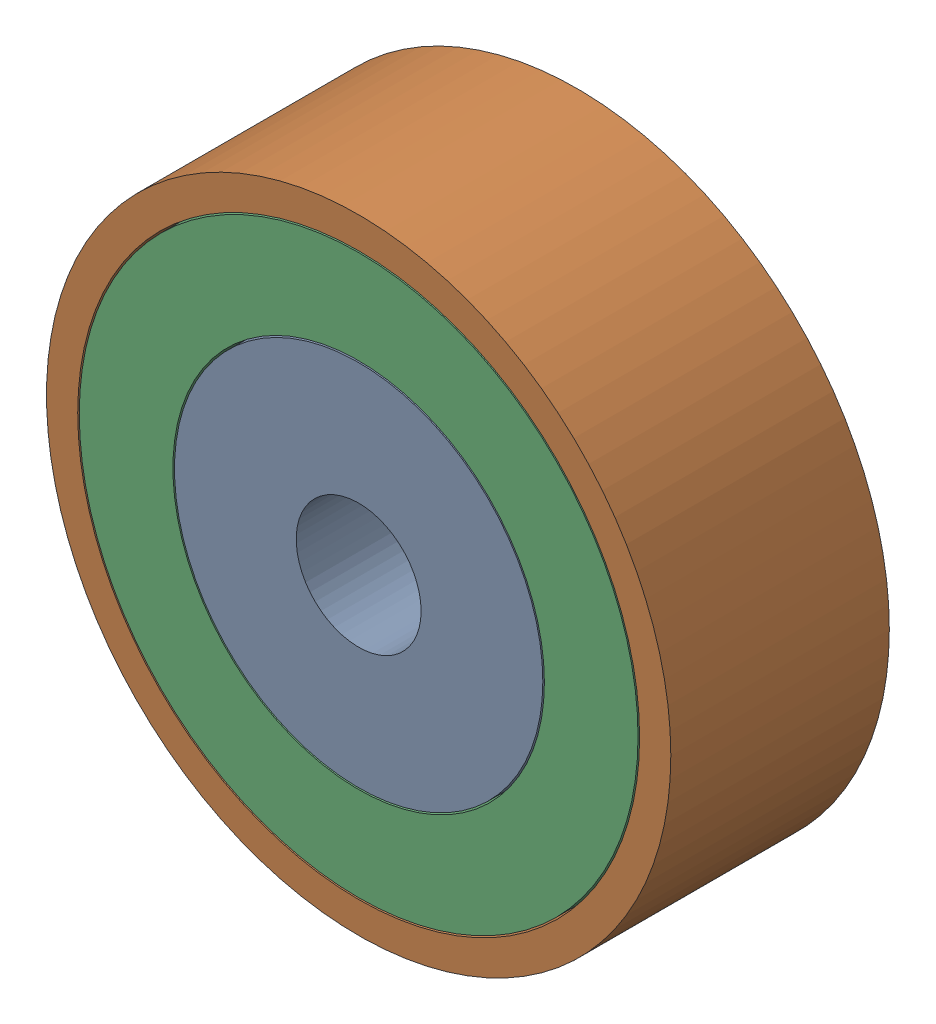
SolidWorks assembly 镜向轴承9, configuration 默认. Lengths in mm.
Overall size (20 20 7).
3 component instances, 3 part files, 4 mates.
Components (placement in the parent):
- 镜向轴承内圈-1: 镜向轴承内圈 [默认] at (-5.0655 0.8032 -6.5) size (11.8 11.8 7)
- 镜向轴承外圈-1: 镜向轴承外圈 [默认] at (-5.0655 0.8032 -6.5) size (20 20 7)
- 镜向轴承中圈-1: 镜向轴承中圈 [默认] at (-5.0655 0.8032 -6.5) size (17.9 17.9 7)
Mates (geometry in assembly coordinates):
- 重合1: coincident: plane of ? through (-5.0655 0.8032 -13.5) normal (0 0 -1); plane of ? through (-5.0655 0.8032 -13.5) normal (0 0 -1)
- 重合2: coincident: plane of ? through (-5.0655 0.8032 -13.5) normal (0 0 -1); plane of ? through (-5.0655 0.8032 -13.5) normal (0 0 -1)
- 同心1: concentric: cylinder of ? through (-5.0655 0.8032 -13.5) axis (0 0 1) radius 9; cylinder of ? through (-5.0655 0.8032 -13.5) axis (0 0 1) radius 8.95
- 同心2: concentric: cylinder of ? through (-5.0655 0.8032 -13.5) axis (0 0 1) radius 5.9; cylinder of ? through (-5.0655 0.8032 -13.5) axis (0 0 1) radius 5.95
